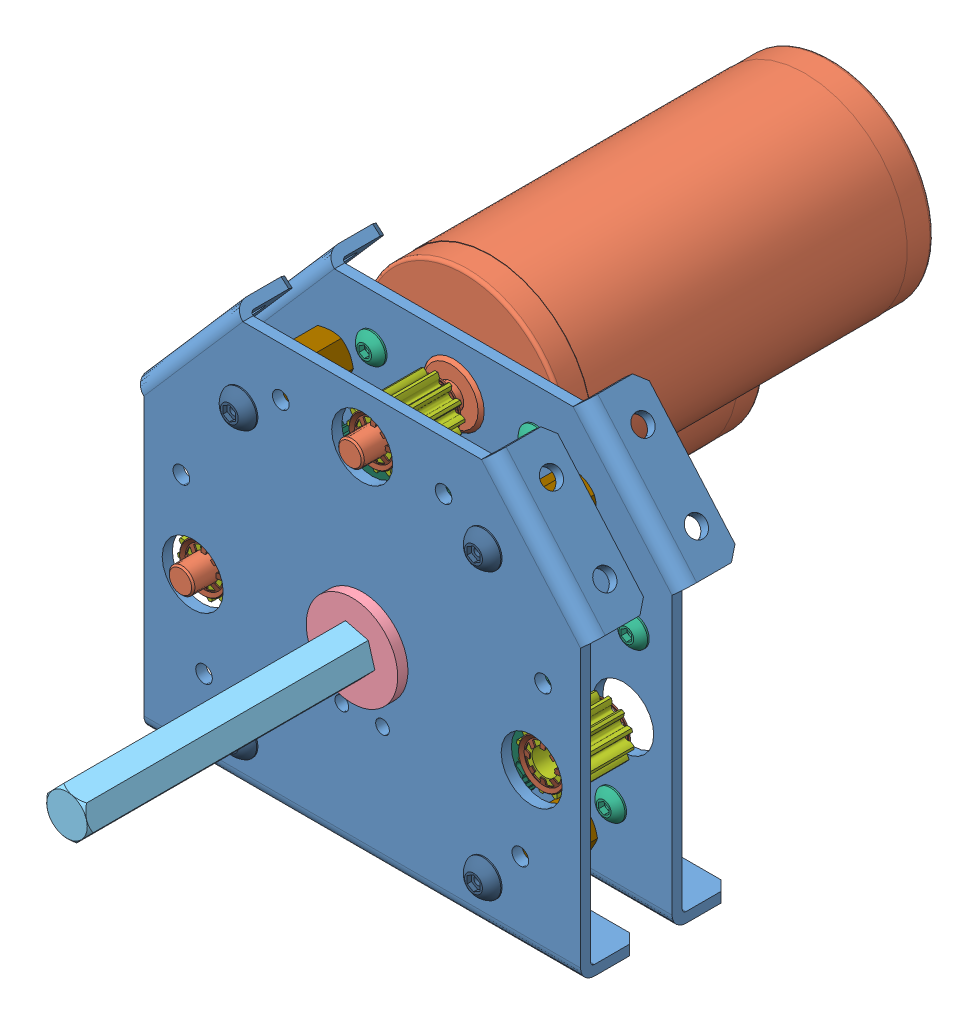
SolidWorks assembly Single Speed, Single Reduction 6-1 72-12 217-2748, configuration Default. Lengths in mm.
Overall size (160.5 152.49 243.24).
43 component instances, 15 part files, 0 mates.
Components (placement in the parent):
- 217-2748-001 Rev1-1: 217-2748-001 Rev1 [Default] at origin size (142.91 129.27 18.42)
- 217-2748-001 Rev1-2: 217-2748-001 Rev1 [Default] at (0 0 28.575) size (142.91 129.27 18.42)
- 217-2000 - CIM Motor-1: 217-2000 - CIM Motor [Default] at (60.2852 -27.4369 -19.05) x (-0.139173 0.990268 0) z (0 0 1) size (64.01 64.01 154.93)
- 217-2000 - CIM Motor-2: 217-2000 - CIM Motor [Default] at (35.56 162.7124 -19.05) x (-1 0 0) z (0 0 1) size (64.01 64.01 154.93)
- 217-2731-1: 217-2731 [Default] at (0 0 -3.175) x (1 0 0) z (0 -1 0) size (31.12 7.94 31.12)
- 217-2734-1: 217-2734 [Default] at (0 0 34.925) x (-0.970869 0.239612 0) z (-0.239612 -0.970869 0) size (31.12 7.94 31.12)
- 217-2454-004 Rev1-1: 217-2454-004 Rev1 [Default] at (0 0 60.3758) x (0 0 1) z (-0.692944 -0.720991 0) size (140.21 12.7 16.13)
- SBS1_SBS1032-0500ZC-1: SBS1_SBS1032-0500ZC [Default] at (-25.4 53.4162 5.7404) x (0 0 -1) z (1 0 0) size (15.78 9.29 9.24)
- 217-2614-001_12t-1: 217-2614-001_12t [Default] at (0 53.4162 18.1045) x (0 1 0) z (0 0 1) size (18.29 18.29 19)
- 217-2737 Rev1-1: 217-2737 Rev1 [Default] at (0 0 11.1633) x (0.85668 -0.515848 0) z (0 0 1) size (25.39 25.4 7.82)
- 217-2617-002 Rev1_91780A359-1: 217-2617-002 Rev1_91780A359 [Default] at (38.1 -43.815 15.875) x (0.856767 0.515704 0) z (0 0 1) size (12.7 14.66 25.4)
- SBS1_SBS2520-0500SS-1: SBS1_SBS2520-0500SS [Default] at (38.1 45.085 -3.3528) x (0 0 1) z (-0.923728 -0.383049 0) size (16.73 11.22 11.17)
- 217-2617-002 Rev1_91780A359-2: 217-2617-002 Rev1_91780A359 [Default] at (38.1 45.085 15.875) size (12.7 14.66 25.4)
- 217-2617-002 Rev1_91780A359-3: 217-2617-002 Rev1_91780A359 [Default] at (-38.1 -43.815 15.875) x (0.856767 0.515704 0) z (0 0 1) size (12.7 14.66 25.4)
- 217-2617-002 Rev1_91780A359-4: 217-2617-002 Rev1_91780A359 [Default] at (-38.1 45.085 15.875) x (0.856767 0.515704 0) z (0 0 1) size (12.7 14.66 25.4)
- SBS1_SBS2520-0500SS-2: SBS1_SBS2520-0500SS [Default] at (38.1 45.085 35.1028) x (0 0 -1) z (1 0 0) size (16.73 11.22 11.17)
- SBS1_SBS2520-0500SS-3: SBS1_SBS2520-0500SS [Default] at (-38.1 -43.815 35.1028) x (0 0 -1) z (1 0 0) size (16.73 11.22 11.17)
- SBS1_SBS2520-0500SS-4: SBS1_SBS2520-0500SS [Default] at (-38.1 45.085 35.1028) x (0 0 -1) z (1 0 0) size (16.73 11.22 11.17)
- SBS1_SBS2520-0500SS-5: SBS1_SBS2520-0500SS [Default] at (38.1 -43.815 35.1028) x (0 0 -1) z (1 0 0) size (16.73 11.22 11.17)
- SBS1_SBS2520-0500SS-6: SBS1_SBS2520-0500SS [Default] at (38.1 -43.815 -3.3528) x (0 0 1) z (0.95771 0.287735 0) size (16.73 11.22 11.17)
- SBS1_SBS2520-0500SS-7: SBS1_SBS2520-0500SS [Default] at (-38.1 -43.815 -3.3528) x (0 0 1) z (0.95771 0.287735 0) size (16.73 11.22 11.17)
- SBS1_SBS2520-0500SS-8: SBS1_SBS2520-0500SS [Default] at (-38.1 45.085 -3.3528) x (0 0 1) z (0.95771 0.287735 0) size (16.73 11.22 11.17)
- 217-2614-001_12t-2: 217-2614-001_12t [Default] at (-52.8964 -7.4341 18.1045) x (0.990268 0.139173 0) z (0 0 1) size (18.29 18.29 19)
- 217-2614-001_12t-3: 217-2614-001_12t [Default] at (52.8964 -7.4341 18.1045) x (0.990268 -0.139173 0) z (0 0 1) size (18.29 18.29 19)
- 217-2614-002_98430A132-1: 217-2614-002_98430A132 [Default] at (-52.8964 -7.4341 27.6041) x (0 0 1) z (-1 0 0) size (1.2 14.83 14.83)
- 217-2614-002_98430A132-2: 217-2614-002_98430A132 [Default] at (-52.8964 -7.4341 7.5381) x (0 0 1) z (-1 0 0) size (1.2 14.83 14.83)
- 217-2614-002_98430A132-3: 217-2614-002_98430A132 [Default] at (0 53.4162 27.6041) x (0 0 1) z (-1 0 0) size (1.2 14.83 14.83)
- 217-2614-002_98430A132-4: 217-2614-002_98430A132 [Default] at (0 53.4162 7.5381) x (0 0 1) z (-1 0 0) size (1.2 14.83 14.83)
- 217-2614-002_98430A132-5: 217-2614-002_98430A132 [Default] at (52.8964 -7.4341 27.6041) x (0 0 1) z (-1 0 0) size (1.2 14.83 14.83)
- 217-2614-002_98430A132-6: 217-2614-002_98430A132 [Default] at (52.8964 -7.4341 7.5381) x (0 0 1) z (-1 0 0) size (1.2 14.83 14.83)
- SBS1_SBS1032-0500ZC-2: SBS1_SBS1032-0500ZC [Default] at (25.4 53.4162 5.7404) x (0 0 -1) z (1 0 0) size (15.78 9.29 9.24)
- SBS1_SBS1032-0500ZC-3: SBS1_SBS1032-0500ZC [Default] at (56.4314 17.7187 5.7404) x (0 0 -1) z (1 0 0) size (15.78 9.29 9.24)
- SBS1_SBS1032-0500ZC-4: SBS1_SBS1032-0500ZC [Default] at (49.3614 -32.5869 5.7404) x (0 0 -1) z (1 0 0) size (15.78 9.29 9.24)
- SBS1_SBS1032-0500ZC-5: SBS1_SBS1032-0500ZC [Default] at (-49.3614 -32.5869 5.7404) x (0 0 -1) z (1 0 0) size (15.78 9.29 9.24)
- SBS1_SBS1032-0500ZC-6: SBS1_SBS1032-0500ZC [Default] at (-56.4314 17.7187 5.7404) x (0 0 -1) z (1 0 0) size (15.78 9.29 9.24)
- 217-2745-002 Rev1-1: 217-2745-002 Rev1 [Default] at (0 0 -39.6748) size (25.4 38.1 1.57)
- 217-2428-005 Rev1-1: 217-2428-005 Rev1 [Default] at (6.35 -19.05 -19.05) x (0.995022 0.099653 0) z (-0.099653 0.995022 0) size (7.33 38.98 6.35)
- 217-2428-005 Rev1-2: 217-2428-005 Rev1 [Default] at (-6.35 -19.05 -19.05) x (0.995022 0.099653 0) z (-0.099653 0.995022 0) size (7.33 38.98 6.35)
- SBS1_SBS0832-0500SS-1: SBS1_SBS0832-0500SS [Default] at (-6.35 -19.05 -41.8846) x (0 0 1) z (-1 0 0) size (15.36 8.02 7.99)
- SBS1_SBS0832-0500SS-2: SBS1_SBS0832-0500SS [Default] at (6.35 -19.05 -41.8846) x (0 0 1) z (-1 0 0) size (15.36 8.02 7.99)
- SBS1_SBS0832-0500SS-3: SBS1_SBS0832-0500SS [Default] at (6.35 -19.05 5.3848) x (0 0 -1) z (1 0 0) size (15.36 8.02 7.99)
- SBS1_SBS0832-0500SS-4: SBS1_SBS0832-0500SS [Default] at (-6.35 -19.05 5.3848) x (0 0 -1) z (1 0 0) size (15.36 8.02 7.99)
- 217-2716-001_72t-1: 217-2716-001_72t [Default] at (0 0 20.6629) x (0.720991 -0.692944 0) z (0 0 1) size (94.86 94.86 12.65)
